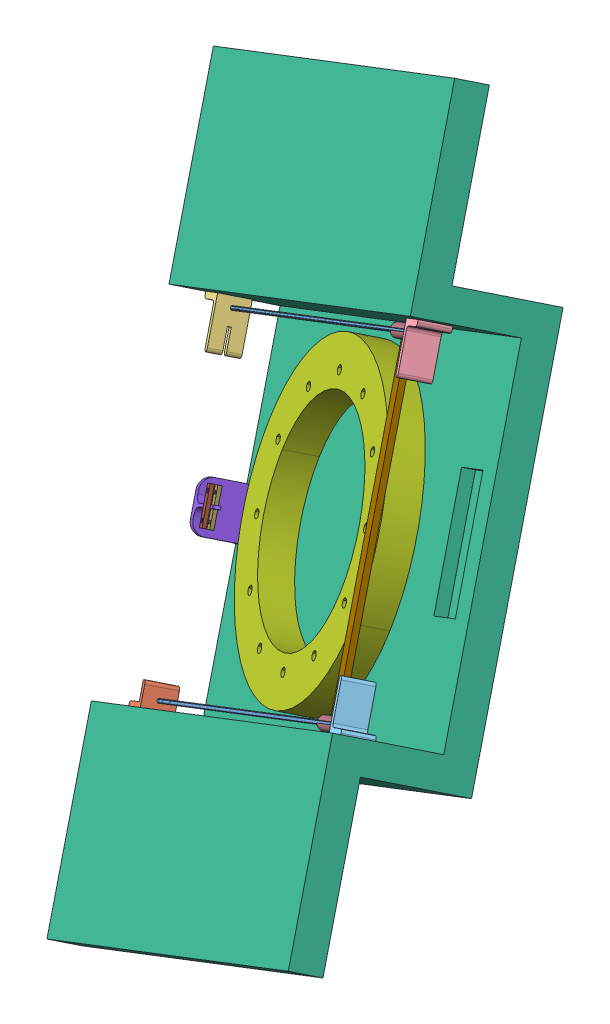
SolidWorks assembly R-01-01, configuration Default. Lengths in mm.
Overall size (587.99 736.87 546.03).
16 component instances, 13 part files, 0 mates.
Components (placement in the parent):
- couverture_anneau.STEP-1: couverture_anneau.STEP [Default] at origin size (587.99 736.87 546.03)
  - tige.STEP-1: tige.STEP [Default] at (92.3943 116.8748 -274.4975) x (-0.456696 0.865255 -0.206792) z (0.37015 -0.026558 -0.928592) size (3.18 356 3.17)
  - tige.STEP-2: tige.STEP [Default] at (154.4063 -55.1619 -157.7952) x (-0.58786 0.687392 0.426513) z (-0.001708 0.526178 -0.850373) size (3.18 356 3.17)
  - braquette3.STEP-1: braquette3.STEP [Default] at (0.6109 -142.9251 -150.3977) x (-0.283104 0.791161 -0.54214) z (0.515203 -0.351333 -0.781749) size (20 22 25)
  - braquette4.STEP-1: braquette4.STEP [Default] at (-67.3341 46.9536 -280.5113) x (-0.283104 0.791161 -0.54214) z (0.515203 -0.351333 -0.781749) size (39.83 22 25)
  - braquette5.STEP-1: braquette5.STEP [Default] at (211.0117 235.9632 -150.0354) x (-0.283104 0.791161 -0.54214) z (-0.515203 0.351333 0.781749) size (39.83 51.31 25)
  - braquette6.STEP-1: braquette6.STEP [Default] at (280.5127 68.9476 -61.1512) x (0.283104 -0.791161 0.54214) z (0.515203 -0.351333 -0.781749) size (39.83 52 25)
  - Plancher.STEP-1: Plancher.STEP [Default] at (380.5379 -77.2334 134.4251) x (-0.283104 0.791161 -0.54214) z (-0.808961 -0.500629 -0.308145) size (600 105 450)
  - anneau_rover.STEP-1: anneau_rover.STEP [Default] at (120.0458 46.252 -195.0808) x (0.159305 0.93548 -0.315435) z (0.842133 0.037976 0.537931) size (255.02 26.67 255.02)
  - basesnapfit.STEP-1: basesnapfit.STEP [Default] at (-31.0478 -36.113 -257.641) x (0.283104 -0.791161 0.54214) z (-0.808961 -0.500629 -0.308145) size (40 42 55)
  - tigecouv.STEP-1: tigecouv.STEP [Default] at (254.0241 36.9822 -45.0866) x (0.808961 0.500629 0.308145) z (-0.515203 0.351333 0.781749) size (10 253 5)
  - interfacema01.STEP-1: interfacema01.STEP [Default] at (1.7119 -41.5536 -233.6059) x (-0.283104 0.791161 -0.54214) z (-0.515203 0.351333 0.781749) size (30 10 5)
  - interfacema02.STEP-1: interfacema02.STEP [Default] at (-20.5713 -28.537 -202.974) x (-0.283104 0.791161 -0.54214) z (0.808961 0.500629 0.308145) size (30 3 5)
  - interfacema03.STEP-1: interfacema03.STEP [Default] at (-17.7377 -30.4693 -207.2736) x (-0.283104 0.791161 -0.54214) z (0.808961 0.500629 0.308145) size (30 3 5)
  - wagon2 - Copy.STEP-1: wagon2 - Copy.STEP [Default] at (240.3514 30.5481 -47.3362) x (0.283104 -0.791161 0.54214) z (0.808961 0.500629 0.308145) size (18 11 40)
  - wagon2 - Copy.STEP-2: wagon2 - Copy.STEP [Default] at (201.044 250.712 -172.1873) x (-0.283104 0.791161 -0.54214) z (-0.808961 -0.500629 -0.308145) size (18 11 40)
